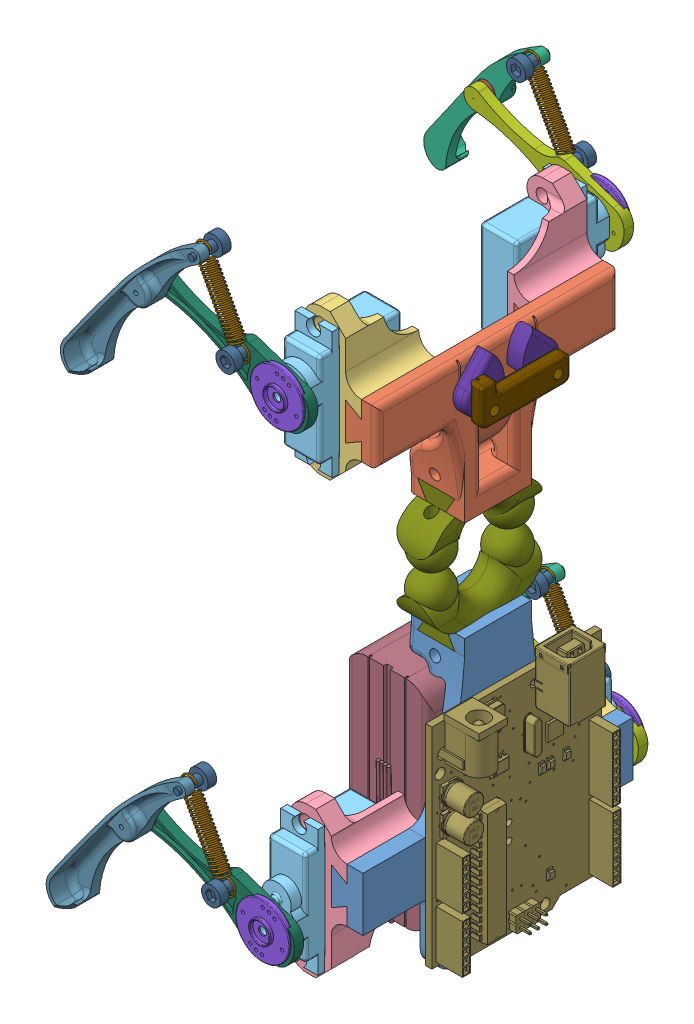
SolidWorks assembly puppy_v04_flexSpine, configuration Default. Lengths in mm.
Overall size (91.8 214.96 133.4).
49 component instances, 18 part files, 53 mates.
Components (placement in the parent):
- body_front-1: body_front [Default] at (3.2532 -96.6244 15.9989) x (0 0 1) z (1 0 0) size (85 87.52 18)
- body_rear-1: body_rear [Default] at (3.2532 44.8839 15.9989) x (0 0 -1) z (1 0 0) size (76 45 18.96)
- HS-81MG_holder_empty-1: HS-81MG_holder_empty [Default] at (-5.7468 -92.6244 -21.5011) x (0 1 0) z (-1 0 0) size (46 23 17.9)
- HS-81MG_holder_empty-2: HS-81MG_holder_empty [Default] at (-5.7468 40.8839 48.9989) x (0 -1 0) z (-1 0 0) size (46 23 17.9)
- HS-81MG_holder_empty_mirror-1: HS-81MG_holder_empty_mirror [Default] at (-5.7468 -92.6244 53.4989) x (0 -1 0) z (-1 0 0) size (46 23 17.9)
- HS-81MG_holder_empty_mirror-2: HS-81MG_holder_empty_mirror [Default] at (-5.7468 40.8839 -17.0011) x (0 1 0) z (-1 0 0) size (46 23 17.9)
- HS-81MG-1: HS-81MG [Default] at (-5.7468 -92.6244 -19.5511) x (0 -1 0) z (1 0 0) size (39.8 33.1 11.7)
- HS-81MG-2: HS-81MG [Default] at (-5.7468 40.8839 -15.0511) x (0 1 0) z (-1 0 0) size (39.8 33.1 11.7)
- HS-81MG-3: HS-81MG [Default] at (-5.7468 -92.6244 51.5489) x (0 -1 0) z (-1 0 0) size (39.8 33.1 11.7)
- HS-81MG-4: HS-81MG [Default] at (-5.7468 40.8839 47.0489) x (0 1 0) z (1 0 0) size (39.8 33.1 11.7)
- AssemblyLeg_v2_left-1: AssemblyLeg_v2_left [Default] at (-28.7433 64.962 -38.46) x (0.571744 0.820432 0) z (-0.820432 0.571744 0) size (58.7 15.8 54.03)
  - LowerLeg_v2_left-1: LowerLeg_v2_left [Standard] at (-46.982 -8.259 12.3103) size (57 10 9.24)
  - UpperLeg_v2_left-1: UpperLeg_v2_left [Standard] at (-2.5862 -3.259 -29.832) x (-0.284896 0 0.958558) z (0 -1 0) size (52.5 13 3)
  - HS-81MG_horn-1: HS-81MG_horn [Default] at (-2.5862 -2.759 -29.832) x (-0.284896 0 0.958558) z (0 -1 0) size (17 17 5)
  - spring-2: spring [Default] at (-2.1428 -2.8777 -14.7648) x (0 1 0) z (0.451588 0 0.892227) size (5 5.5 30.5)
  - Schraube-2: Schraube [Standard] at (-3.2717 -0.159 -16.9953) x (0 -1 0) z (-0.448796 0 0.893634) size (9.7 6 6)
  - Schraube-3: Schraube [Standard] at (8.018 -5.359 5.3103) x (0 1 0) z (0.208882 0 0.977941) size (9.7 6 6)
  - spacerM3_1mm-1: spacerM3_1mm [Default] at (-13.982 -3.259 8.5103) x (1 0 0) z (0 1 0) size (6 6 1)
- AssemblyLeg_v2_left-2: AssemblyLeg_v2_left [Default] at (-28.6007 -78.1766 -42.96) x (0.577801 0.816178 0) z (-0.816178 0.577801 0) size (58.7 15.8 54.03)
  - LowerLeg_v2_left-1: LowerLeg_v2_left [Standard] at (-46.982 -8.259 12.3103) size (57 10 9.24)
  - UpperLeg_v2_left-1: UpperLeg_v2_left [Standard] at (-2.5862 -3.259 -29.832) x (-0.284896 0 0.958558) z (0 -1 0) size (52.5 13 3)
  - HS-81MG_horn-1: HS-81MG_horn [Default] at (-2.5862 -2.759 -29.832) x (-0.284896 0 0.958558) z (0 -1 0) size (17 17 5)
  - spring-2: spring [Default] at (-2.1428 -2.8777 -14.7648) x (0 1 0) z (0.451588 0 0.892227) size (5 5.5 30.5)
  - Schraube-2: Schraube [Standard] at (-3.2717 -0.159 -16.9953) x (0 -1 0) z (-0.448796 0 0.893634) size (9.7 6 6)
  - Schraube-3: Schraube [Standard] at (8.018 -5.359 5.3103) x (0 1 0) z (0.208882 0 0.977941) size (9.7 6 6)
  - spacerM3_1mm-1: spacerM3_1mm [Default] at (-13.982 -3.259 8.5103) x (1 0 0) z (0 1 0) size (6 6 1)
- arduino-1: arduino [Default] at (12.2532 -48.5844 38.819) x (0 -1 0) z (0 0 1) size (74.75 15.48 53.34)
- 1350 mAh 25C LiPo-1: 1350 mAh 25C LiPo [Default] at (7.2532 -45.2433 -1.0011) x (0 0 -1) z (0 1 0) size (38.93 26 69.53)
- AssemblyLeg_v2_right-1: AssemblyLeg_v2_right [Default] at (-28.6981 -78.2922 70.44) x (0.573673 0.819084 0) z (-0.819084 0.573673 0) size (59.24 15.8 54.03)
  - LowerLeg_v2_right-1: LowerLeg_v2_right [Standard] at (-46.982 -8.259 12.3103) size (57 10 9.24)
  - UpperLeg_v2_right-1: UpperLeg_v2_right [Standard] at (-2.5862 4.741 -29.832) x (-0.284896 0 0.958558) z (0 -1 0) size (52.5 13 3)
  - HS-81MG_horn-1: HS-81MG_horn [Default] at (-2.5862 -1.759 -29.832) x (-0.284896 0 0.958558) z (0 1 0) size (17 17 5)
  - spring-2: spring [Default] at (-2.1428 -2.0089 -14.7648) x (0 1 0) z (0.451588 0 0.892227) size (5 5.5 30.5)
  - Schraube-2: Schraube [Standard] at (-3.2717 -4.359 -16.9953) x (0 1 0) z (-0.11305 0 0.993589) size (9.7 6 6)
  - Schraube-3: Schraube [Standard] at (8.018 0.841 5.3103) x (0 -1 0) z (-0.709749 0 0.704455) size (9.7 6 6)
  - spacerM3_1mm-1: spacerM3_1mm [Default] at (-13.982 -2.259 8.5103) x (1 0 0) z (0 1 0) size (6 6 1)
- AssemblyLeg_v2_right-2: AssemblyLeg_v2_right [Default] at (-28.6424 65.0823 65.94) x (0.576038 0.817423 0) z (-0.817423 0.576038 0) size (59.24 15.8 54.03)
  - LowerLeg_v2_right-1: LowerLeg_v2_right [Standard] at (-46.982 -8.259 12.3103) size (57 10 9.24)
  - UpperLeg_v2_right-1: UpperLeg_v2_right [Standard] at (-2.5862 4.741 -29.832) x (-0.284896 0 0.958558) z (0 -1 0) size (52.5 13 3)
  - HS-81MG_horn-1: HS-81MG_horn [Default] at (-2.5862 -1.759 -29.832) x (-0.284896 0 0.958558) z (0 1 0) size (17 17 5)
  - spring-2: spring [Default] at (-2.1428 -2.0089 -14.7648) x (0 1 0) z (0.451588 0 0.892227) size (5 5.5 30.5)
  - Schraube-2: Schraube [Standard] at (-3.2717 -4.359 -16.9953) x (0 1 0) z (-0.11305 0 0.993589) size (9.7 6 6)
  - Schraube-3: Schraube [Standard] at (8.018 0.841 5.3103) x (0 -1 0) z (-0.709749 0 0.704455) size (9.7 6 6)
  - spacerM3_1mm-1: spacerM3_1mm [Default] at (-13.982 -2.259 8.5103) x (1 0 0) z (0 1 0) size (6 6 1)
- spine-1: spine [Default] at (3.2532 -21.6244 15.9989) x (0 0 1) z (-1 0 0) size (36 20.75 12.69)
- spine-2: spine [Default] at (3.2532 -10.1161 15.9989) x (0 0 -1) z (-1 0 0) size (36 20.75 12.69)
- holder_part-1: holder_part [Default] at (14.7532 29.2275 6.0729) x (0 -0.716295 -0.697797) z (1 0 0) size (15 10 5)
- holder_part-2: holder_part [Default] at (14.7532 29.2366 25.671) x (0 -0.746912 0.664923) z (-1 0 0) size (15 10 5)
- holder_top-1: holder_top [Default] at (19.2532 34.8839 15.9989) x (0 0 1) z (1 0 0) size (28 11.81 4)
Mates (geometry in assembly coordinates):
- Coincident10: coincident anti-aligned: plane of body_rear-1 through (2.2532 30.4971 30.9989) normal (-1 0 0); plane of HS-81MG_holder_empty-2 through (2.2532 42.1833 4.7) normal (1 0 0)
- Coincident11: coincident anti-aligned: plane of body_rear-1 through (7.2532 33.3839 30.9989) normal (0.5 -0.866025 0); plane of HS-81MG_holder_empty-2 through (15.9868 38.4263 19.3692) normal (-0.5 0.866025 0)
- Coincident12: coincident anti-aligned: line of body_rear-1 through (2.2532 42.2706 53.9989) axis (0.866025 -0.5 0); line of HS-81MG_holder_empty-2 through (7.2532 39.3839 53.9989) axis (-0.866025 0.5 0)
- Coincident13: coincident anti-aligned: plane of body_front-1 through (2.2532 -82.2376 58.4989) normal (-1 0 0); plane of HS-81MG_holder_empty_mirror-1 through (2.2532 -91.3249 9.2) normal (1 0 0)
- Coincident14: coincident anti-aligned: plane of body_front-1 through (7.2532 -85.1244 58.4989) normal (0.5 0.866025 0); plane of HS-81MG_holder_empty_mirror-1 through (-2.6324 -79.4169 23.8692) normal (-0.5 -0.866025 0)
- Coincident15: coincident anti-aligned: line of body_front-1 through (2.2532 -94.0111 58.4989) axis (0.866025 0.5 0); line of HS-81MG_holder_empty_mirror-1 through (7.2532 -91.1244 58.4989) axis (-0.866025 -0.5 0)
- Coincident16: coincident anti-aligned: plane of body_rear-1 through (2.2532 30.4971 0.9989) normal (-1 0 0); plane of HS-81MG_holder_empty_mirror-2 through (2.2532 39.5845 27.2979) normal (1 0 0)
- Coincident17: coincident anti-aligned: plane of body_rear-1 through (2.2532 42.2706 0.9989) normal (0.5 0.866025 0); plane of HS-81MG_holder_empty_mirror-2 through (15.9868 34.3415 12.6286) normal (-0.5 -0.866025 0)
- Coincident18: coincident aligned: line of body_rear-1 through (7.2532 33.3839 -22.0011) axis (-0.866025 -0.5 0); line of HS-81MG_holder_empty_mirror-2 through (7.2532 33.3839 -22.0011) axis (-0.866025 -0.5 0)
- Coincident19: coincident anti-aligned: plane of body_front-1 through (2.2532 -82.2376 58.4989) normal (-1 0 0); plane of HS-81MG_holder_empty-1 through (2.2532 -93.9238 22.7979) normal (1 0 0)
- Coincident20: coincident anti-aligned: plane of body_front-1 through (7.2532 -85.1244 58.4989) normal (0.5 0.866025 0); plane of HS-81MG_holder_empty-1 through (15.9868 -90.1667 8.1286) normal (-0.5 -0.866025 0)
- Coincident23: coincident anti-aligned: line of body_front-1 through (2.2532 -94.0111 -26.5011) axis (0.866025 0.5 0); line of HS-81MG_holder_empty-1 through (7.2532 -91.1244 -26.5011) axis (-0.866025 -0.5 0)
- Coincident24: coincident anti-aligned: plane of HS-81MG_holder_empty-1 through (-13.7468 -93.9238 -26.5011) normal (0 0 -1); plane of HS-81MG-1 through (0.1032 -112.5244 -26.5011) normal (0 0 1)
- Concentric1: concentric aligned: cylinder of HS-81MG_holder_empty-1 through (-5.7468 -110.7244 -6.5011) axis (0 0 -1) radius 2; cylinder of HS-81MG-1 through (-5.7468 -110.7244 -20.1371) axis (0 0 -1) radius 2.25
- Concentric2: concentric aligned: cylinder of HS-81MG_holder_empty-1 through (-5.7468 -74.5244 -6.5011) axis (0 0 -1) radius 2; cylinder of HS-81MG-1 through (-5.7468 -74.5244 -20.1371) axis (0 0 -1) radius 2.25
- Coincident25: coincident anti-aligned: plane of HS-81MG_holder_empty_mirror-2 through (-13.7468 39.5845 -22.0011) normal (0 0 -1); plane of HS-81MG-2 through (-11.5968 60.7839 -22.0011) normal (0 0 1)
- Concentric3: concentric aligned: cylinder of HS-81MG_holder_empty_mirror-2 through (-5.7468 22.7839 -2.0011) axis (0 0 -1) radius 2; cylinder of HS-81MG-2 through (-5.7468 22.7839 -15.6371) axis (0 0 -1) radius 2.25
- Concentric4: concentric aligned: cylinder of HS-81MG_holder_empty_mirror-2 through (-5.7468 58.9839 -2.0011) axis (0 0 -1) radius 2; cylinder of HS-81MG-2 through (-5.7468 58.9839 -15.6371) axis (0 0 -1) radius 2.25
- Coincident26: coincident anti-aligned: plane of HS-81MG_holder_empty_mirror-1 through (-13.7468 -91.3249 58.4989) normal (0 0 1); plane of HS-81MG-3 through (-11.5968 -72.7244 58.4989) normal (0 0 -1)
- Concentric5: concentric aligned: cylinder of HS-81MG_holder_empty_mirror-1 through (-5.7468 -74.5244 38.4989) axis (0 0 1) radius 2; cylinder of HS-81MG-3 through (-5.7468 -74.5244 52.135) axis (0 0 1) radius 2.25
- Concentric6: concentric aligned: cylinder of HS-81MG_holder_empty_mirror-1 through (-5.7468 -110.7244 38.4989) axis (0 0 1) radius 2; cylinder of HS-81MG-3 through (-5.7468 -110.7244 52.135) axis (0 0 1) radius 2.25
- Coincident27: coincident anti-aligned: plane of HS-81MG_holder_empty-2 through (-13.7468 42.1833 53.9989) normal (0 0 1); plane of HS-81MG-4 through (0.1032 60.7839 53.9989) normal (0 0 -1)
- Concentric7: concentric aligned: cylinder of HS-81MG_holder_empty-2 through (-5.7468 22.7839 33.9989) axis (0 0 1) radius 2; cylinder of HS-81MG-4 through (-5.7468 22.7839 47.635) axis (0 0 1) radius 2.25
- Concentric8: concentric aligned: cylinder of HS-81MG_holder_empty-2 through (-5.7468 58.9839 33.9989) axis (0 0 1) radius 2; cylinder of HS-81MG-4 through (-5.7468 58.9839 47.635) axis (0 0 1) radius 2.25
- Coincident30: coincident anti-aligned: plane of body_front-1 through (12.2532 -96.6244 15.9989) normal (1 0 0); plane of arduino-1 through (12.2532 -15 12.1306) normal (-1 0 0)
- Concentric11: concentric anti-aligned: cylinder of body_front-1 through (7.2532 -114.6244 31.199) axis (1 0 0) radius 1.5; cylinder of arduino-1 through (14.2532 -114.6244 31.199) axis (-1 0 0) radius 1.6
- Concentric12: concentric anti-aligned: cylinder of body_front-1 through (7.2532 -114.6244 3.259) axis (1 0 0) radius 1.5; cylinder of arduino-1 through (14.2532 -114.6244 3.259) axis (-1 0 0) radius 1.6
- Concentric13: concentric anti-aligned: cylinder of AssemblyLeg_v2_left-2/HS-81MG_horn-1 through (-5.7468 -97.5244 -38.7011) axis (0 0 -1) radius 2.5; cylinder of HS-81MG-1 through (-5.7468 -97.5244 -39.7011) axis (0 0 1) radius 1.5
- Coincident34: coincident anti-aligned: plane of HS-81MG-1 through (-5.7468 -97.5244 -39.7011) normal (0 0 -1); plane of AssemblyLeg_v2_left-2/HS-81MG_horn-1 through (-5.7468 -97.5244 -39.7011) normal (0 0 1)
- Concentric14: concentric anti-aligned: cylinder of HS-81MG-2 through (-5.7468 45.7839 -35.2011) axis (0 0 1) radius 1.5; cylinder of AssemblyLeg_v2_left-1/HS-81MG_horn-1 through (-5.7468 45.7839 -34.2011) axis (0 0 -1) radius 2.5
- Coincident35: coincident anti-aligned: plane of HS-81MG-2 through (-5.7468 45.7839 -35.2011) normal (0 0 -1); plane of AssemblyLeg_v2_left-1/HS-81MG_horn-1 through (-5.7468 45.7839 -35.2011) normal (0 0 1)
- Concentric15: concentric anti-aligned: cylinder of HS-81MG-3 through (-5.7468 -97.5244 71.6989) axis (0 0 -1) radius 1.5; cylinder of AssemblyLeg_v2_right-1/HS-81MG_horn-1 through (-5.7468 -97.5244 70.6989) axis (0 0 1) radius 2.5
- Coincident36: coincident anti-aligned: plane of HS-81MG-3 through (-5.7468 -97.5244 71.6989) normal (0 0 1); plane of AssemblyLeg_v2_right-1/HS-81MG_horn-1 through (-5.7468 -97.5244 71.6989) normal (0 0 -1)
- Concentric16: concentric anti-aligned: cylinder of HS-81MG-4 through (-5.7468 45.7839 67.1989) axis (0 0 -1) radius 1.5; cylinder of AssemblyLeg_v2_right-2/HS-81MG_horn-1 through (-5.7468 45.7839 66.1989) axis (0 0 1) radius 2.5
- Coincident37: coincident anti-aligned: plane of HS-81MG-4 through (-5.7468 45.7839 67.1989) normal (0 0 1); plane of AssemblyLeg_v2_right-2/HS-81MG_horn-1 through (-5.7468 45.7839 67.1989) normal (0 0 -1)
- Coincident38: coincident anti-aligned: plane of body_front-1 through (12.2532 -36.6244 15.9989) normal (0 1 0); plane of spine-1 through (-2.6336 -36.6244 5.4989) normal (0 -1 0)
- Coincident39: coincident anti-aligned: plane of body_front-1 through (6.2532 -31.6244 26.4989) normal (-0.866025 -0.5 0); plane of spine-1 through (9.1399 -36.6244 5.4989) normal (0.866025 0.5 0)
- Coincident40: coincident anti-aligned: line of body_front-1 through (6.2532 -31.6244 5.4989) axis (0.5 -0.866025 0); line of spine-1 through (9.1399 -36.6244 5.4989) axis (-0.5 0.866025 0)
- Coincident41: coincident anti-aligned: plane of body_rear-1 through (12.2532 4.8839 16.41) normal (0 -1 0); plane of spine-2 through (-2.6336 4.8839 26.4989) normal (0 1 0)
- Coincident42: coincident anti-aligned: plane of body_rear-1 through (6.2532 -0.1161 5.4989) normal (-0.866025 0.5 0); plane of spine-2 through (9.1399 4.8839 26.4989) normal (0.866025 -0.5 0)
- Coincident43: coincident anti-aligned: line of body_rear-1 through (6.2532 -0.1161 5.4989) axis (0.5 0.866025 0); line of spine-2 through (9.1399 4.8839 5.4989) axis (-0.5 -0.866025 0)
- Coincident44: coincident anti-aligned: circle of spine-1; circle of spine-2
- Coincident45: coincident anti-aligned: circle of spine-1; circle of spine-2
- Concentric18: concentric aligned: cylinder of body_rear-1 through (-9.9895 34.8839 5.9989) axis (1 0 0) radius 1.5; cylinder of holder_part-1 through (5.1821 34.8839 5.9989) axis (1 0 0) radius 1.5
- Coincident46: coincident anti-aligned: plane of body_rear-1 through (12.2532 -39.4637 16.41) normal (1 0 0); plane of holder_part-1 through (12.2532 37.9962 0.6545) normal (-1 0 0)
- Concentric19: concentric anti-aligned: cylinder of body_rear-1 through (-9.9895 34.8839 25.9989) axis (1 0 0) radius 1.5; cylinder of holder_part-2 through (24.3242 34.8839 25.9989) axis (-1 0 0) radius 1.5
- Coincident47: coincident anti-aligned: plane of body_rear-1 through (12.2532 -39.4637 16.41) normal (1 0 0); plane of holder_part-2 through (12.2532 37.7531 31.4778) normal (-1 0 0)
- Coincident48: coincident anti-aligned: plane of holder_part-2 through (17.2532 37.7531 31.4778) normal (1 0 0); plane of holder_top-1 through (17.2532 60.1759 17.1125) normal (-1 0 0)
- Concentric20: concentric aligned: cylinder of holder_part-2 through (24.3242 34.8839 25.9989) axis (-1 0 0) radius 1.5; cylinder of holder_top-1 through (21.2532 34.8839 25.9989) axis (-1 0 0) radius 1.5
- Concentric21: concentric anti-aligned: cylinder of holder_part-1 through (5.1821 34.8839 5.9989) axis (1 0 0) radius 1.5; cylinder of holder_top-1 through (21.2532 34.8839 5.9989) axis (-1 0 0) radius 1.5
- Coincident49: coincident: plane of body_front-1 through (7.2532 -96.6244 15.9989) normal (-1 0 0); plane of 1350 mAh 25C LiPo-1 through (7.2532 -115.6937 -1.0011) normal (1 0 0)
- Width2: width: plane of body_front-1 through (3.2532 -96.6244 -3.5011) normal (0 0 1); plane of body_front-1 through (3.2532 -96.6244 35.4989) normal (0 0 -1); plane of 1350 mAh 25C LiPo-1 through (7.2532 -113.2433 -1.0011) normal (0 0 -1); plane of 1350 mAh 25C LiPo-1 through (7.2532 -113.2433 32.9989) normal (0 0 1)
- Tangent3: tangent anti-aligned: cylinder of body_front-1 through (3.2532 -40.6244 -3.5011) axis (0 0 1) radius 5; cylinder of 1350 mAh 25C LiPo-1 through (0.2532 -52.2433 -1.0011) axis (0 0 -1) radius 7
